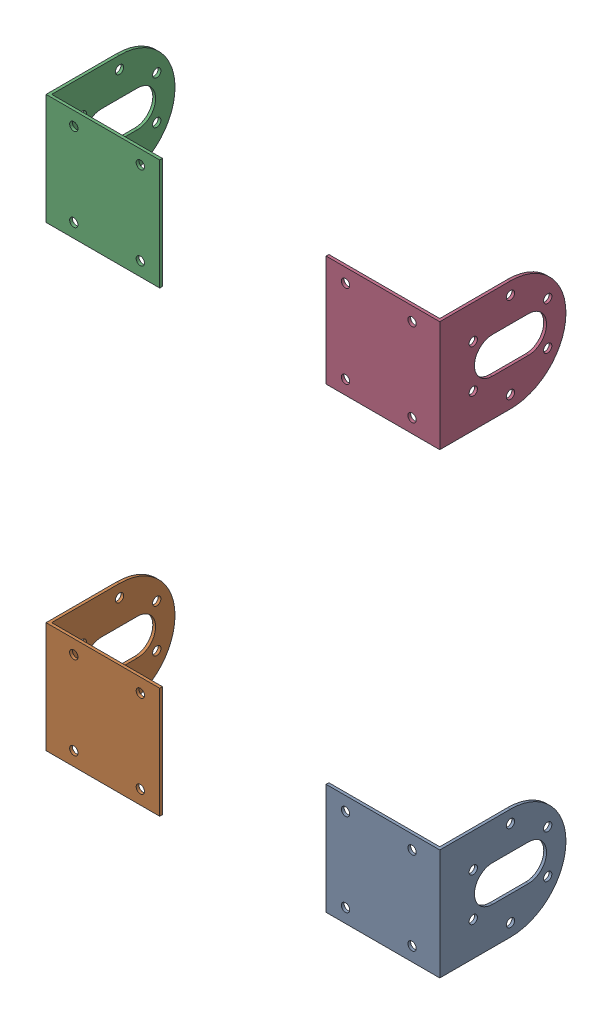
SolidWorks assembly Motor Brackets, configuration Varsayılan. Lengths in mm.
Overall size (142 205 45.5).
4 component instances, 4 part files, 0 mates.
Components (placement in the parent):
- Motor Bracket_001-1: Motor Bracket_001 [Varsayılan] at (71 -115.5 -4) x (-1 0 0) z (0 0 -1) size (41 40 45.5)
- Motor Bracket_002-1: Motor Bracket_002 [Varsayılan] at (-71 -115.5 -4) x (1 0 0) z (0 0 -1) size (41 40 45.5)
- Motor Bracket_003-1: Motor Bracket_003 [Varsayılan] at (-71 49.5 -4) x (1 0 0) z (0 0 -1) size (41 40 45.5)
- Motor Bracket_004-1: Motor Bracket_004 [Varsayılan] at (71 49.5 -4) x (-1 0 0) z (0 0 -1) size (41 40 45.5)
